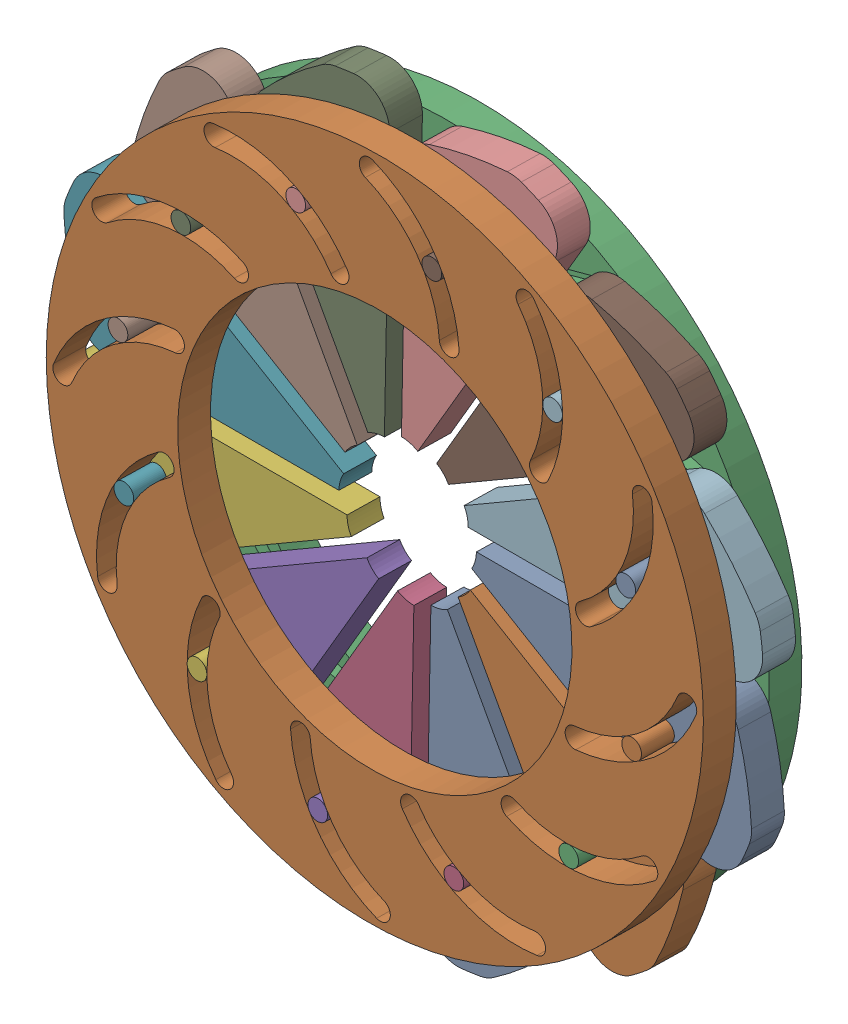
SolidWorks assembly Jadon's praxis assembly 2, configuration Default. Lengths in mm.
Overall size (14.11 14.11 1.77).
26 component instances, 4 part files, 12 mates.
Components (placement in the parent):
- Jadon's shutter blade v3-1: Jadon's shutter blade v3 [Default] at (0.3719 -0.4038 0.5081) x (-0.696253 -0.717657 0.014142) z (-0.717796 0.696118 -0.013717) size (3.23 0.7 3.88)
- Jadon's disk v2-1: Jadon's disk v2 [Default] at (0 0.0296 1.4997) x (0.889523 0.456802 -0.009001) z (-0.45689 0.88935 -0.017525) size (10 0.5 10)
- Jadon's shutter sandwich circle-2: Jadon's shutter sandwich circle [Default] at (0 0.0099 0.4999) x (0.755633 0.654869 -0.012904) z (-0.654996 0.755486 -0.014887) size (10 0.5 10)
- Jadon's Shutter pins-2: Jadon's Shutter pins [Default] at (1.2778 -3.7839 0.5747) x (0.864822 0.501982 -0.009892) z (0 0.019702 0.999806) size (0.3 0.3 1)
- Jadon's Shutter pins-3: Jadon's Shutter pins [Default] at (-0.7906 -3.9144 0.5772) x (0.999997 0.002402 -0.000047) z (0 0.019702 0.999806) size (0.3 0.3 1)
- Jadon's Shutter pins-4: Jadon's Shutter pins [Default] at (-2.6472 -2.9934 0.5591) x (0.867224 -0.497821 0.00981) z (0 0.019702 0.999806) size (0.3 0.3 1)
- Jadon's Shutter pins-5: Jadon's Shutter pins [Default] at (-3.7944 -1.2677 0.5251) x (0.502079 -0.864654 0.017038) z (0 0.019702 0.999806) size (0.3 0.3 1)
- Jadon's Shutter pins-6: Jadon's Shutter pins [Default] at (-3.925 0.8003 0.4843) x (0.002403 -0.999803 0.019701) z (0 0.019702 0.999806) size (0.3 0.3 1)
- Jadon's Shutter pins-7: Jadon's Shutter pins [Default] at (-3.0038 2.6565 0.4477) x (-0.497918 -0.867056 0.017086) z (0 0.019702 0.999806) size (0.3 0.3 1)
- Jadon's Shutter pins-8: Jadon's Shutter pins [Default] at (-1.2778 3.8036 0.4251) x (-0.864822 -0.501982 0.009892) z (0 0.019702 0.999806) size (0.3 0.3 1)
- Jadon's Shutter pins-9: Jadon's Shutter pins [Default] at (0.7906 3.9341 0.4226) x (-0.999997 -0.002402 0.000047) z (0 0.019702 0.999806) size (0.3 0.3 1)
- Jadon's Shutter pins-10: Jadon's Shutter pins [Default] at (2.6472 3.0131 0.4407) x (-0.867224 0.497821 -0.00981) z (0 0.019702 0.999806) size (0.3 0.3 1)
- Jadon's Shutter pins-11: Jadon's Shutter pins [Default] at (3.7944 1.2874 0.4747) x (-0.502079 0.864654 -0.017038) z (0 0.019702 0.999806) size (0.3 0.3 1)
- Jadon's Shutter pins-12: Jadon's Shutter pins [Default] at (3.925 -0.7806 0.5155) x (-0.002403 0.999803 -0.019701) z (0 0.019702 0.999806) size (0.3 0.3 1)
- Jadon's Shutter pins-13: Jadon's Shutter pins [Default] at (3.0038 -2.6368 0.5521) x (0.497918 0.867056 -0.017086) z (0 0.019702 0.999806) size (0.3 0.3 1)
- Jadon's shutter blade v3-2: Jadon's shutter blade v3 [Default] at (0.1152 -0.5343 0.5106) x (-0.961871 -0.27345 0.005388) z (-0.273503 0.961684 -0.01895) size (3.23 0.7 3.88)
- Jadon's shutter blade v3-3: Jadon's shutter blade v3 [Default] at (-0.1723 -0.519 0.5103) x (-0.969756 0.244028 -0.004809) z (0.244075 0.969568 -0.019106) size (3.23 0.7 3.88)
- Jadon's shutter blade v3-4: Jadon's shutter blade v3 [Default] at (-0.4137 -0.362 0.5072) x (-0.717796 0.696118 -0.013717) z (0.696253 0.717657 -0.014142) size (3.23 0.7 3.88)
- Jadon's shutter blade v3-5: Jadon's shutter blade v3 [Default] at (-0.5442 -0.1054 0.5022) x (-0.273503 0.961684 -0.01895) z (0.961871 0.27345 -0.005388) size (3.23 0.7 3.88)
- Jadon's shutter blade v3-6: Jadon's shutter blade v3 [Default] at (-0.5289 0.1821 0.4965) x (0.244075 0.969568 -0.019106) z (0.969756 -0.244028 0.004809) size (3.23 0.7 3.88)
- Jadon's shutter blade v3-7: Jadon's shutter blade v3 [Default] at (-0.3719 0.4235 0.4918) x (0.696253 0.717657 -0.014142) z (0.717796 -0.696118 0.013717) size (3.23 0.7 3.88)
- Jadon's shutter blade v3-8: Jadon's shutter blade v3 [Default] at (-0.1152 0.554 0.4892) x (0.961871 0.27345 -0.005388) z (0.273503 -0.961684 0.01895) size (3.23 0.7 3.88)
- Jadon's shutter blade v3-9: Jadon's shutter blade v3 [Default] at (0.1723 0.5387 0.4895) x (0.969756 -0.244028 0.004809) z (-0.244075 -0.969568 0.019106) size (3.23 0.7 3.88)
- Jadon's shutter blade v3-10: Jadon's shutter blade v3 [Default] at (0.4137 0.3817 0.4926) x (0.717796 -0.696118 0.013717) z (-0.696253 -0.717657 0.014142) size (3.23 0.7 3.88)
- Jadon's shutter blade v3-11: Jadon's shutter blade v3 [Default] at (0.5442 0.1251 0.4976) x (0.273503 -0.961684 0.01895) z (-0.961871 -0.27345 0.005388) size (3.23 0.7 3.88)
- Jadon's shutter blade v3-12: Jadon's shutter blade v3 [Default] at (0.5289 -0.1624 0.5033) x (-0.244075 -0.969568 0.019106) z (-0.969756 0.244028 -0.004809) size (3.23 0.7 3.88)
Mates (geometry in assembly coordinates):
- Coincident13: coincident anti-aligned: plane of Jadon's shutter blade v3-1 through (1.5407 -2.8375 0.356) normal (-0.258819 0.965738 -0.01903); plane of Jadon's shutter sandwich circle-2 through (0.9725 -2.9898 0.359) normal (0.258819 -0.965738 0.01903)
- Coincident22: coincident anti-aligned: plane of Jadon's shutter blade v3-1 through (0.3719 -0.4038 0.5081) normal (0 -0.019702 -0.999806); plane of Jadon's shutter sandwich circle-2 through (0 0.0099 0.4999) normal (0 0.019702 0.999806)
- Concentric5: concentric aligned: cylinder of Jadon's shutter blade v3-1 through (1.2778 -3.7445 2.5743) axis (0 -0.019702 -0.999806) radius 0.15; cylinder of Jadon's Shutter pins-2 through (1.2778 -3.7642 1.5745) axis (0 -0.019702 -0.999806) radius 0.15
- Concentric6: concentric aligned: cylinder of Jadon's disk v2-1 through (0 0.0197 0.9998) axis (0 0.019702 0.999806) radius 3; cylinder of Jadon's shutter sandwich circle-2 through (0 0 0) axis (0 0.019702 0.999806) radius 3
- Parallel8: parallel anti-aligned: plane of Jadon's shutter blade v3-1 through (0.3719 -0.3939 1.008) normal (-1 0 0)
- Coincident25: coincident anti-aligned: plane of Jadon's shutter blade v3-1 through (0.3719 -0.3939 1.008) normal (0 0.019702 0.999806); plane of Jadon's disk v2-1 through (0 0.0197 0.9998) normal (0 -0.019702 -0.999806)
- Concentric9: concentric aligned: cylinder of Jadon's shutter blade v3-1 through (1.2778 -3.7445 2.5743) axis (0 -0.019702 -0.999806) radius 0.15; cylinder of Jadon's Shutter pins-2 through (1.2778 -3.7642 1.5745) axis (0 -0.019702 -0.999806) radius 0.15
- Tangent8: tangent aligned: cylinder of Jadon's disk v2-1 through (2.241 -2.0216 1.04) axis (0 0.019702 0.999806) radius 2.15; cylinder of Jadon's Shutter pins-2 through (1.2778 -3.7642 1.5745) axis (0 -0.019702 -0.999806) radius 0.15
- Coincident28: coincident aligned: plane of Jadon's disk v2-1 through (0 0.0296 1.4997) normal (0 0.019702 0.999806); plane of Jadon's Shutter pins-2 through (1.2778 -3.7642 1.5745) normal (0 0.019702 0.999806)
- Parallel13: parallel anti-aligned: cylinder of Jadon's disk v2-1 through (2.241 -2.0216 1.04) axis (0 0.019702 0.999806) radius 2.15; cylinder of Jadon's Shutter pins-2 through (1.2778 -3.7642 1.5745) axis (0 -0.019702 -0.999806) radius 0.15
- Coincident29: coincident: plane of Jadon's shutter sandwich circle-2 through (0 0 0) normal (0 -0.019702 -0.999806)
- Concentric14: concentric aligned: cylinder of Jadon's disk v2-1 through (0 0.0197 0.9998) axis (0 0.019702 0.999806) radius 3
